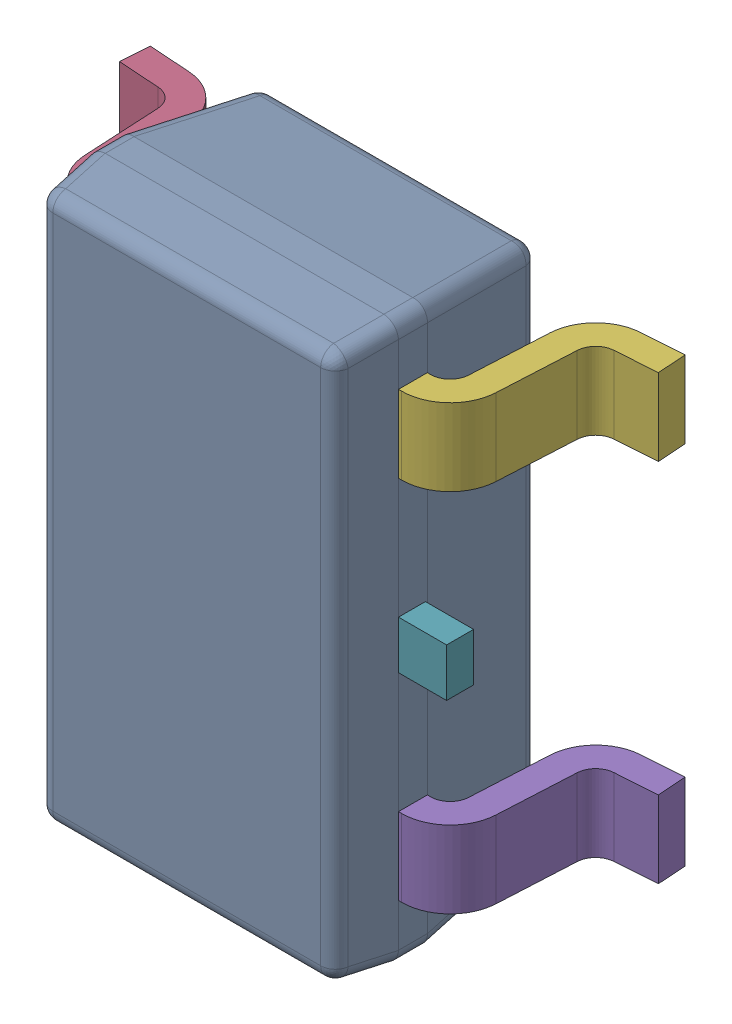
SolidWorks assembly 6348792768_1.step, configuration Default. Lengths in mm.
Overall size (2.8 2.9 1.2).
7 component instances, 3 part files, 0 mates.
Components (placement in the parent):
- BODY-SOT-1213_1.step-3: BODY-SOT-1213_1.step [Default] at (0 0 0.9) x (0 -1 0) z (-1 0 0) size (2.9 1.1 1.6)
- LEAD-SOT-1214_1.step-21: LEAD-SOT-1214_1.step [Default] at (-0.9395 -0.95 0.25) x (0 -1 0) z (-1 0 0) size (0.4 0.9 0.6)
- LEAD-SOT-1214_1.step-22: LEAD-SOT-1214_1.step [Default] at (-0.9395 0 0.25) x (0 -1 0) z (-1 0 0) size (0.4 0.9 0.6)
- LEAD-SOT-1214_1.step-23: LEAD-SOT-1214_1.step [Default] at (-0.9395 0.95 0.25) x (0 -1 0) z (-1 0 0) size (0.4 0.9 0.6)
- LEAD-SOT-1214_1.step-24: LEAD-SOT-1214_1.step [Default] at (0.9395 -0.95 0.25) x (0 1 0) z (1 0 0) size (0.4 0.9 0.6)
- LEAD-SOT-1214_1.step-25: LEAD-SOT-1214_1.step [Default] at (0.9395 0.95 0.25) x (0 1 0) z (1 0 0) size (0.4 0.9 0.6)
- LEAD-DUMMY-1215_1.step-3: LEAD-DUMMY-1215_1.step [Default] at (1.05 0 0.76) x (0 -1 0) z (-1 0 0) size (0.25 0.14 0.25)
